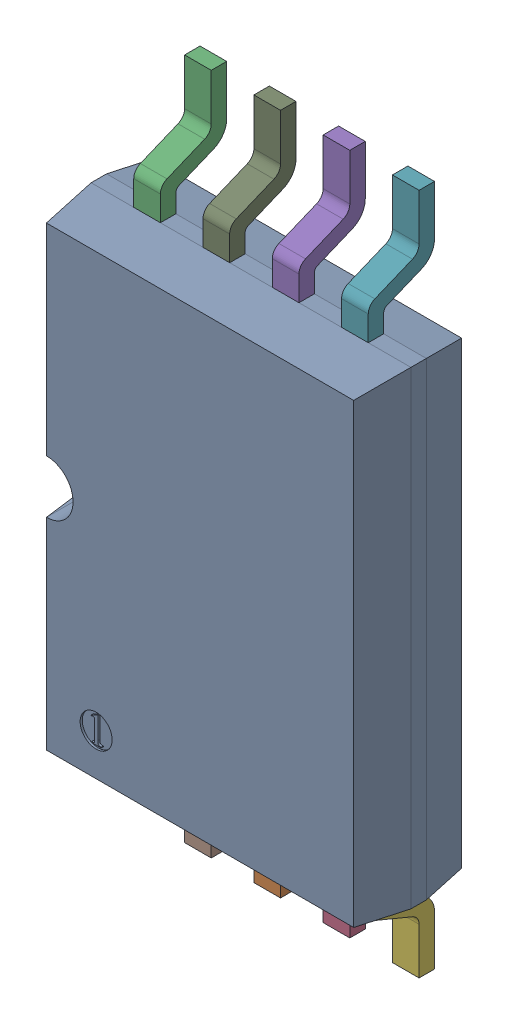
SolidWorks assembly U3.step, configuration Default. Lengths in mm.
Overall size (3 6.4 1.1).
10 component instances, 2 part files, 0 mates.
Components (placement in the parent):
- tssop8_model.step-1: tssop8_model.step [Default] at (58.974 52.84 1.25) x (1 0 0) z (0 -1 0) size (3 1.1 6.4)
  - tssop8_body.step-1: tssop8_body.step [Default] at (-1.8727 -0.8115 1.5395) size (3 1 4.4)
  - pin5to8_tssop8.step-1: pin5to8_tssop8.step [Default] at (-0.5727 -0.6665 1.5395) x (-1 0 0) z (0 0 -1) size (0.25 0.62 1.2)
  - pin5to8_tssop8.step-2: pin5to8_tssop8.step [Default] at (-1.4727 -0.6665 -2.8605) size (0.25 0.62 1.2)
  - pin5to8_tssop8.step-3: pin5to8_tssop8.step [Default] at (0.0773 -0.6665 1.5395) x (-1 0 0) z (0 0 -1) size (0.25 0.62 1.2)
  - pin5to8_tssop8.step-4: pin5to8_tssop8.step [Default] at (-0.1727 -0.6665 -2.8605) size (0.25 0.62 1.2)
  - pin5to8_tssop8.step-5: pin5to8_tssop8.step [Default] at (0.7273 -0.6665 1.5395) x (-1 0 0) z (0 0 -1) size (0.25 0.62 1.2)
  - pin5to8_tssop8.step-6: pin5to8_tssop8.step [Default] at (0.4773 -0.6665 -2.8605) size (0.25 0.62 1.2)
  - pin5to8_tssop8.step-7: pin5to8_tssop8.step [Default] at (-1.2227 -0.6665 1.5395) x (-1 0 0) z (0 0 -1) size (0.25 0.62 1.2)
  - pin5to8_tssop8.step-8: pin5to8_tssop8.step [Default] at (-0.8227 -0.6665 -2.8605) size (0.25 0.62 1.2)
